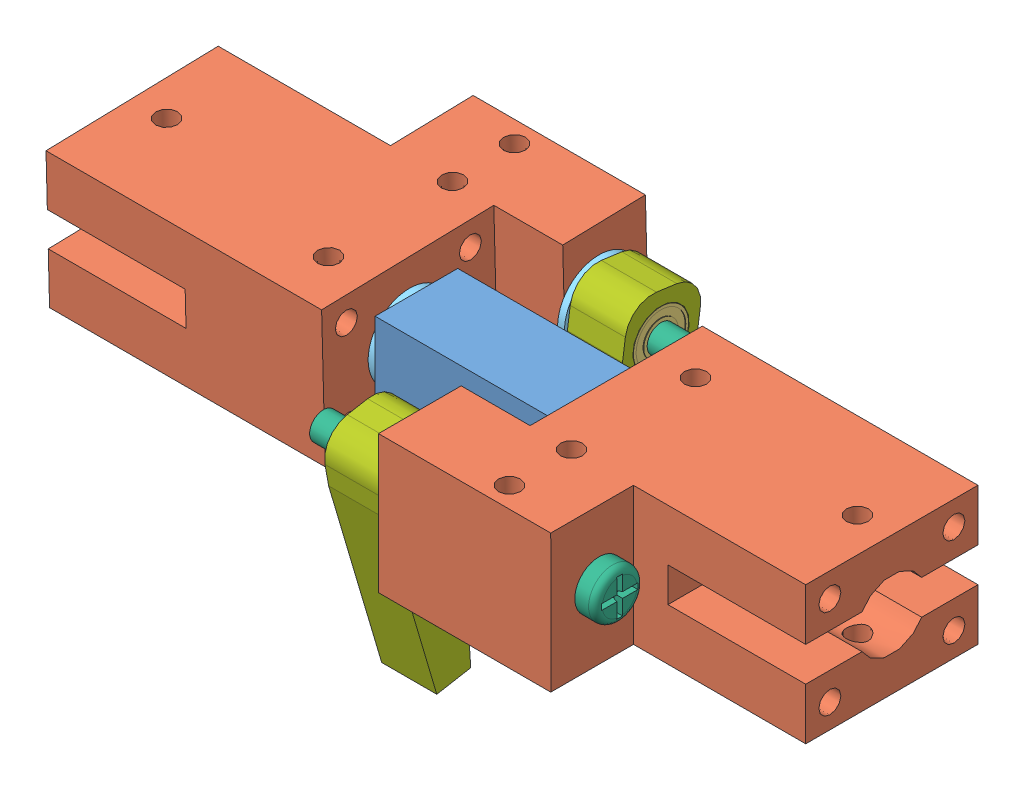
SolidWorks assembly mad_man_rotor_head_assembly, configuration По умолчанию. Lengths in mm.
Overall size (110 39.17 50.51).
20 component instances, 7 part files, 38 mates.
Components (placement in the parent):
- rotor_head-1: rotor_head [По умолчанию] at (16.8576 6.5359 19.7289) size (28 32 12)
- blade_holder-1: blade_holder [По умолчанию] at (-18.1424 42.5326 19.9881) x (1 0 0) z (0 0.025928 -0.999664) size (50 20 37)
- blade_holder-2: blade_holder [По умолчанию] at (51.8576 42.5359 19.7316) x (-1 0 0) z (0 -0.000272 1) size (50 20 37)
- m4x3x8_head_bearing-1: m4x3x8_head_bearing [По умолчанию] at (31.8576 32.5359 19.7289) x (0 -1 0) z (0 0 1) size (8 3 8)
- m4x3x8_head_bearing-2: m4x3x8_head_bearing [По умолчанию] at (1.8576 32.5359 19.7289) x (0 0.396193 -0.918167) z (0 0.918167 0.396193) size (8 3 8)
- m4x3x8_head_bearing-3: m4x3x8_head_bearing [По умолчанию] at (-12.1424 32.5359 19.7289) x (0 0.806508 0.591223) z (0 -0.591223 0.806508) size (8 3 8)
- m4x3x8_head_bearing-4: m4x3x8_head_bearing [По умолчанию] at (45.8576 32.5359 19.7289) x (0 -1 0) z (0 0 1) size (8 3 8)
- m4x65_screw-1: m4x65_screw [По умолчанию] at (-16.1424 32.5359 19.7289) x (0 -0.460919 0.887442) z (0 0.887442 0.460919) size (7.03 68.01 7.03)
- m4_washer-1: m4_washer [По умолчанию] at (31.8576 32.5359 19.7289) x (0 1 0) z (0 0 1) size (12 1 12)
- m4_washer-2: m4_washer [По умолчанию] at (2.8576 32.5359 19.7289) x (0 1 0) z (0 0 1) size (12 1 12)
- m4x3x8_head_bearing-5: m4x3x8_head_bearing [По умолчанию] at (17.8576 32.9897 2.2347) x (0 0.94745 0.319902) z (0 0.319902 -0.94745) size (8 3 8)
- m4x3x8_head_bearing-6: m4x3x8_head_bearing [По умолчанию] at (15.8576 32.5312 37.2289) x (0 -0.724025 0.689774) z (0 -0.689774 -0.724025) size (8 3 8)
- m4x3x8_head_bearing-7: m4x3x8_head_bearing [По умолчанию] at (20.8576 32.5312 37.2289) x (0 0.3814 0.92441) z (0 -0.92441 0.3814) size (8 3 8)
- m4x40_screw-3: m4x40_screw [По умолчанию] at (26.8576 32.9897 2.2347) x (0 1 0) z (0 0 1) size (7.03 43.01 7.03)
- m4x40_screw-4: m4x40_screw [По умолчанию] at (6.8576 32.5312 37.2289) x (0 -1 0) z (0 0 1) size (7.03 43.01 7.03)
- m4_washer-3: m4_washer [По умолчанию] at (11.8576 32.9897 2.2347) x (0 -0.972223 -0.234056) z (0 -0.234056 0.972223) size (12 1 12)
- DFC__head_linkage_dual_bearing_latest-1: DFC__head_linkage_dual_bearing_latest [По умолчанию] at (16.8576 5.2568 6.093) x (0 0.137795 0.990461) z (-1 0 0) size (11 34 8)
- m4x3x8_head_bearing-9: m4x3x8_head_bearing [По умолчанию] at (15.8576 32.9897 2.2347) x (0 0.381233 0.924479) z (0 -0.924479 0.381233) size (8 3 8)
- DFC__head_linkage_dual_bearing_latest-2: DFC__head_linkage_dual_bearing_latest [По умолчанию] at (16.8576 4.9675 32.3048) x (0 -0.175861 0.984415) z (-1 0 0) size (11 34 8)
- m4_washer-4: m4_washer [По умолчанию] at (21.8576 32.5312 37.2289) x (0 0.526217 -0.85035) z (0 0.85035 0.526217) size (12 1 12)
Mates (geometry in assembly coordinates):
- Концентричный1: concentric aligned: cylinder of rotor_head-1 through (30.8576 32.5359 19.7289) axis (-1 0 0) radius 2; cylinder of blade_holder-1 through (1.8576 32.5359 19.7289) axis (-1 0 0) radius 3
- Концентричный2: concentric aligned: cylinder of rotor_head-1 through (30.8576 32.5359 19.7289) axis (-1 0 0) radius 2; cylinder of blade_holder-2 through (34.8576 32.5359 19.7289) axis (-1 0 0) radius 4.1
- Концентричный3: concentric anti-aligned: cylinder of blade_holder-2 through (31.8576 32.5359 19.7289) axis (1 0 0) radius 3; cylinder of m4x3x8_head_bearing-4 through (48.8576 32.5359 19.7289) axis (-1 0 0) radius 2
- Совпадение1: coincident anti-aligned: plane of blade_holder-2 through (45.8576 32.5359 19.7289) normal (1 0 0); plane of m4x3x8_head_bearing-4 through (45.8576 32.5359 19.7289) normal (-1 0 0)
- Концентричный4: concentric anti-aligned: cylinder of blade_holder-2 through (31.8576 32.5359 19.7289) axis (1 0 0) radius 3; cylinder of m4x3x8_head_bearing-1 through (34.8576 32.5359 19.7289) axis (-1 0 0) radius 2
- Совпадение2: coincident anti-aligned: plane of blade_holder-2 through (34.8576 32.5359 19.7289) normal (-1 0 0); plane of m4x3x8_head_bearing-1 through (34.8576 32.5359 19.7289) normal (1 0 0)
- Концентричный6: concentric anti-aligned: cylinder of blade_holder-2 through (31.8576 32.5359 19.7289) axis (1 0 0) radius 3; cylinder of m4x65_screw-1 through (48.8576 32.5359 19.7289) axis (-1 0 0) radius 2
- Совпадение4: coincident anti-aligned: plane of m4x3x8_head_bearing-4 through (48.8576 32.5359 19.7289) normal (1 0 0); plane of m4x65_screw-1 through (48.8576 32.5359 19.7289) normal (-1 0 0)
- Концентричный7: concentric anti-aligned: cylinder of blade_holder-1 through (1.8576 32.5359 19.7289) axis (-1 0 0) radius 3; cylinder of m4x3x8_head_bearing-2 through (-1.1424 32.5359 19.7289) axis (1 0 0) radius 2
- Концентричный8: concentric anti-aligned: cylinder of blade_holder-1 through (1.8576 32.5359 19.7289) axis (-1 0 0) radius 3; cylinder of m4x3x8_head_bearing-3 through (-15.1424 32.5359 19.7289) axis (1 0 0) radius 2
- Совпадение5: coincident anti-aligned: plane of blade_holder-1 through (-1.1424 32.5359 19.7289) normal (1 0 0); plane of m4x3x8_head_bearing-2 through (-1.1424 32.5359 19.7289) normal (-1 0 0)
- Совпадение6: coincident anti-aligned: plane of blade_holder-1 through (-12.1424 32.5359 19.7289) normal (-1 0 0); plane of m4x3x8_head_bearing-3 through (-12.1424 32.5359 19.7289) normal (1 0 0)
- Концентричный9: concentric anti-aligned: cylinder of m4x65_screw-1 through (48.8576 32.5359 19.7289) axis (-1 0 0) radius 2; cylinder of m4_washer-1 through (30.8576 32.5359 19.7289) axis (1 0 0) radius 2
- Концентричный10: concentric anti-aligned: cylinder of m4x65_screw-1 through (48.8576 32.5359 19.7289) axis (-1 0 0) radius 2; cylinder of m4_washer-2 through (1.8576 32.5359 19.7289) axis (1 0 0) radius 2
- Совпадение7: coincident anti-aligned: plane of rotor_head-1 through (2.8576 38.5359 25.7289) normal (-1 0 0); plane of m4_washer-2 through (2.8576 32.5359 19.7289) normal (1 0 0)
- Совпадение9: coincident anti-aligned: plane of rotor_head-1 through (30.8576 38.5359 25.7289) normal (1 0 0); circle of m4_washer-1
- Совпадение10: coincident anti-aligned: plane of blade_holder-2 through (31.8576 22.5325 32.2261) normal (-1 0 0); plane of m4_washer-1 through (31.8576 32.5359 19.7289) normal (1 0 0)
- Совпадение11: coincident anti-aligned: plane of blade_holder-1 through (1.8576 22.8634 6.9738) normal (1 0 0); plane of m4_washer-2 through (1.8576 32.5359 19.7289) normal (-1 0 0)
- Концентричный20: concentric anti-aligned: cylinder of blade_holder-1 through (11.8576 32.9897 2.2347) axis (-1 0 0) radius 2; cylinder of m4x40_screw-3 through (-13.1424 32.9897 2.2347) axis (1 0 0) radius 2
- Совпадение19: coincident anti-aligned: plane of blade_holder-1 through (-13.1424 23.1745 -5.0222) normal (-1 0 0); plane of m4x40_screw-3 through (-13.1424 32.9897 2.2347) normal (1 0 0)
- Концентричный21: concentric anti-aligned: cylinder of blade_holder-2 through (21.8576 32.5312 37.2289) axis (1 0 0) radius 2; cylinder of m4x40_screw-4 through (46.8576 32.5312 37.2289) axis (-1 0 0) radius 2
- Совпадение20: coincident anti-aligned: plane of blade_holder-2 through (46.8576 22.5293 44.2261) normal (1 0 0); plane of m4x40_screw-4 through (46.8576 32.5312 37.2289) normal (-1 0 0)
- Концентричный24: concentric anti-aligned: cylinder of m4x3x8_head_bearing-5 through (20.8576 32.9897 2.2347) axis (-1 0 0) radius 2; cylinder of m4x40_screw-3 through (-13.1424 32.9897 2.2347) axis (1 0 0) radius 2
- Концентричный27: concentric anti-aligned: cylinder of m4x3x8_head_bearing-6 through (12.8576 32.5312 37.2289) axis (1 0 0) radius 2; cylinder of m4x40_screw-4 through (46.8576 32.5312 37.2289) axis (-1 0 0) radius 2
- Концентричный29: concentric anti-aligned: cylinder of m4x40_screw-3 through (-13.1424 32.9897 2.2347) axis (1 0 0) radius 2; cylinder of m4_washer-3 through (12.8576 32.9897 2.2347) axis (-1 0 0) radius 2
- Совпадение24: coincident anti-aligned: plane of blade_holder-1 through (11.8576 43.1678 -4.5036) normal (1 0 0); plane of m4_washer-3 through (11.8576 32.9897 2.2347) normal (-1 0 0)
- Концентричный30: concentric anti-aligned: cylinder of DFC__head_linkage_dual_bearing_latest-1 through (15.8576 32.9897 2.2347) axis (-1 0 0) radius 4.1; cylinder of m4x3x8_head_bearing-9 through (12.8576 32.9897 2.2347) axis (1 0 0) radius 4
- Совпадение26: coincident anti-aligned: plane of DFC__head_linkage_dual_bearing_latest-1 through (15.8576 32.9897 2.2347) normal (-1 0 0); plane of m4x3x8_head_bearing-9 through (15.8576 32.9897 2.2347) normal (1 0 0)
- Концентричный31: concentric anti-aligned: cylinder of m4x3x8_head_bearing-5 through (20.8576 32.9897 2.2347) axis (-1 0 0) radius 4; cylinder of DFC__head_linkage_dual_bearing_latest-1 through (17.8576 32.9897 2.2347) axis (1 0 0) radius 4.1
- Совпадение27: coincident anti-aligned: plane of m4x3x8_head_bearing-5 through (17.8576 32.9897 2.2347) normal (-1 0 0); plane of DFC__head_linkage_dual_bearing_latest-1 through (17.8576 32.9897 2.2347) normal (1 0 0)
- Концентричный32: concentric anti-aligned: cylinder of m4x3x8_head_bearing-7 through (17.8576 32.5312 37.2289) axis (1 0 0) radius 4; cylinder of DFC__head_linkage_dual_bearing_latest-2 through (15.8576 32.5312 37.2289) axis (-1 0 0) radius 4.1
- Совпадение29: coincident anti-aligned: plane of m4x3x8_head_bearing-7 through (17.8576 32.5312 37.2289) normal (-1 0 0); plane of DFC__head_linkage_dual_bearing_latest-2 through (17.8576 32.5312 37.2289) normal (1 0 0)
- Концентричный33: concentric anti-aligned: cylinder of m4x3x8_head_bearing-6 through (12.8576 32.5312 37.2289) axis (1 0 0) radius 4; cylinder of DFC__head_linkage_dual_bearing_latest-2 through (15.8576 32.5312 37.2289) axis (-1 0 0) radius 4.1
- Совпадение30: coincident anti-aligned: plane of m4x3x8_head_bearing-6 through (15.8576 32.5312 37.2289) normal (1 0 0); plane of DFC__head_linkage_dual_bearing_latest-2 through (15.8576 32.5312 37.2289) normal (-1 0 0)
- Концентричный34: concentric anti-aligned: cylinder of m4x40_screw-4 through (46.8576 32.5312 37.2289) axis (-1 0 0) radius 2; cylinder of m4_washer-4 through (20.8576 32.5312 37.2289) axis (1 0 0) radius 2
- Совпадение31: coincident anti-aligned: plane of blade_holder-2 through (21.8576 42.5293 44.2316) normal (-1 0 0); plane of m4_washer-4 through (21.8576 32.5312 37.2289) normal (1 0 0)
- Совпадение32: coincident anti-aligned: plane of DFC__head_linkage_dual_bearing_latest-2 through (20.8576 37.4704 43.6983) normal (1 0 0); plane of m4_washer-4 through (20.8576 32.5312 37.2289) normal (-1 0 0)
- Совпадение34: coincident anti-aligned: plane of m4_washer-3 through (12.8576 32.9897 2.2347) normal (1 0 0); plane of DFC__head_linkage_dual_bearing_latest-1 through (12.8576 39.6903 6.8555) normal (-1 0 0)
